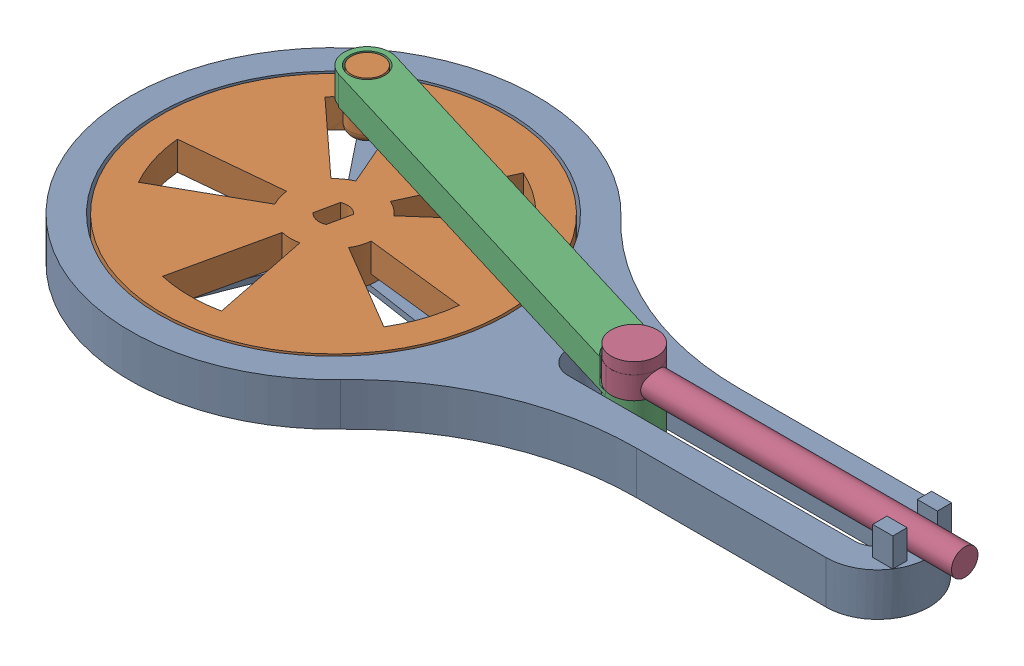
SolidWorks assembly MotorActuatorAssembly_v1.000.001, configuration Default. Lengths in mm.
Overall size (152.1 14.18 84).
4 component instances, 4 part files, 7 mates.
Components (placement in the parent):
- Chassis_v1.000.001-1: Chassis_v1.000.001 [Default] at origin size (139.5 12.5 71)
- Cog-1: Cog [Default] at (-39.1882 0 32.0018) x (0.599956 0 -0.800033) z (0.800033 0 0.599956) size (60 11.56 60)
- Linkage_v1.000.001-1: Linkage_v1.000.001 [Default] at (-23.6931 0 4.518) x (0.998659 0 -0.051772) z (0.051772 0 0.998659) size (73.85 12.5 31.81)
- Presser_v1.000.001-1: Presser_v1.000.001 [Default] at (-20.9521 -0.2 -0.0003) size (61.63 6.7 8.04)
Mates (geometry in assembly coordinates):
- Coincident2: coincident anti-aligned: plane of Chassis_v1.000.001-1 through (12.4055 45.1742 55.1864) normal (0 1 0); plane of Cog-1 through (12.4055 45.1742 55.1864) normal (0 -1 0)
- Concentric1: concentric aligned: cylinder of Cog-1 through (-2.0819 56.8891 34.8121) axis (0 1 0) radius 2.75; cylinder of Linkage_v1.000.001-1 through (-2.0819 56.8891 34.8121) axis (0 1 0) radius 3.0628
- Concentric2: concentric aligned: cylinder of Linkage_v1.000.001-1 through (64.8935 56.3914 55.1661) axis (0 -1 0) radius 3.4622; cylinder of Presser_v1.000.001-1 through (64.8935 56.0711 55.1661) axis (0 -1 0) radius 3.4622
- Coincident3: coincident anti-aligned: plane of Linkage_v1.000.001-1 through (72.9688 52.4499 28.6231) normal (0 1 0); plane of Presser_v1.000.001-1 through (72.192 52.4499 28.3991) normal (0 -1 0)
- Tangent3: tangent anti-aligned: plane of Chassis_v1.000.001-1 through (12.4055 51.6742 51.1864) normal (0 0 1); cylinder of Linkage_v1.000.001-1 through (64.8874 56.6742 55.1864) axis (0 -1 0) radius 4
- Concentric3: concentric aligned: cylinder of Chassis_v1.000.001-1 through (12.4055 46.6742 55.1864) axis (0 -1 0) radius 5; circle of Cog-1
- Concentric4: concentric anti-aligned: cylinder of Chassis_v1.000.001-1 through (12.4055 51.6742 55.1864) axis (0 -1 0) radius 30.5; circle of Cog-1
